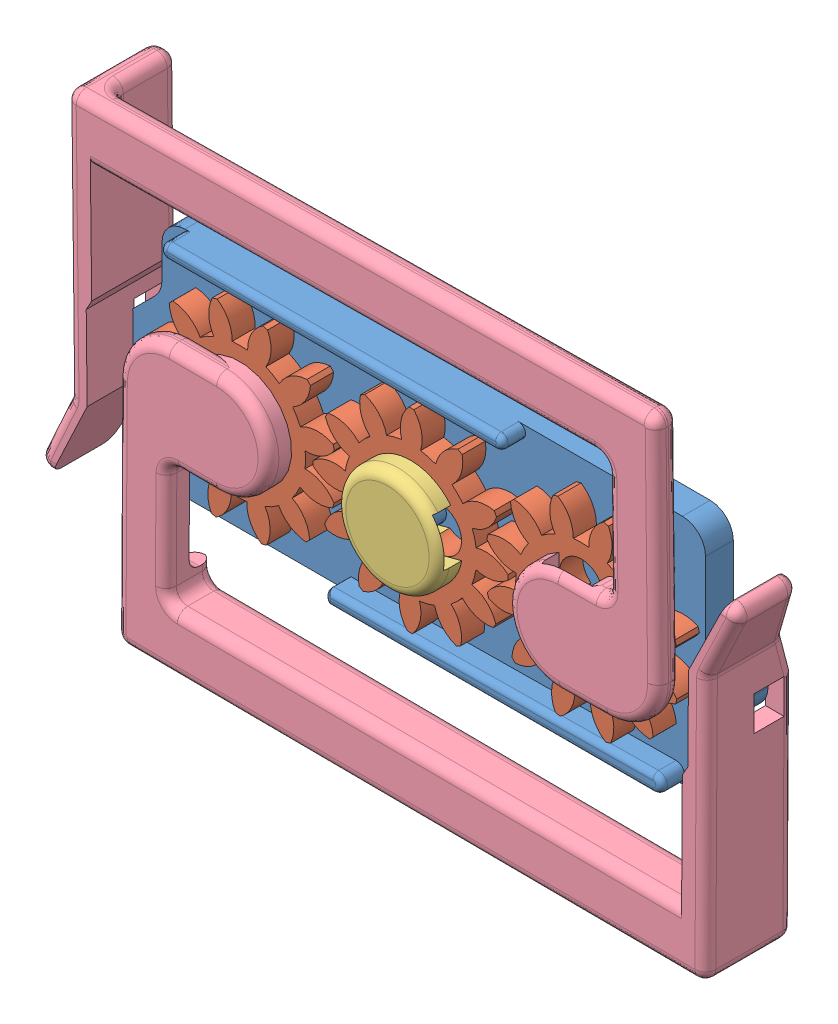
SolidWorks assembly WebCoupler, configuration Default. Lengths in mm.
Overall size (76.9 51.21 9.65).
7 component instances, 4 part files, 17 mates.
Components (placement in the parent):
- BasePlate-1: BasePlate [Default] at (-2.9894 14.8162 46.0364) size (67.3 25.47 7.37)
- WebGear-1: WebGear [Default] at (26.8556 27.5162 51.6244) x (0.251002 -0.967986 0) z (0 0 -1) size (20.81 20.81 2.54)
- WebGear-2: WebGear [Default] at (45.6516 27.5162 51.6244) x (0.999938 0.011168 0) z (0 0 -1) size (20.81 20.81 2.54)
- WebGear-3: WebGear [Default] at (8.0596 27.5162 51.6244) x (-0.999982 0.00603 0) z (0 0 -1) size (20.81 20.81 2.54)
- CapturePlate-1: CapturePlate [Default] at (27.6271 28.2686 54.1644) x (0.251002 -0.967986 0) z (0 0 -1) size (11.42 11.3 5.08)
- WebArm-2: WebArm [Default] at (8.6151 26.6036 54.1644) x (-0.999982 0.00603 0) z (0 0 -1) size (67.99 37.46 9.65)
- WebArm-4: WebArm [Default] at (45.0804 28.4191 54.1644) x (0.999938 0.011168 0) z (0 0 -1) size (67.99 37.46 9.65)
Mates (geometry in assembly coordinates):
- Coincident1: coincident anti-aligned: plane of BasePlate-1 through (-2.9894 14.8162 49.0844) normal (0 0 1); plane of WebGear-3 through (10.1295 31.2966 49.0844) normal (0 0 -1)
- Concentric2: concentric anti-aligned: cylinder of BasePlate-1 through (8.0596 27.5162 51.7514) axis (0 0 -1) radius 1.397; cylinder of WebGear-3 through (8.0596 27.5162 49.0844) axis (0 0 1) radius 1.524
- Coincident2: coincident anti-aligned: plane of BasePlate-1 through (-2.9894 14.8162 49.0844) normal (0 0 1); plane of WebGear-1 through (22.6703 28.5457 49.0844) normal (0 0 -1)
- Concentric3: concentric anti-aligned: cylinder of BasePlate-1 through (26.8556 27.5162 51.7514) axis (0 0 -1) radius 1.397; cylinder of WebGear-1 through (26.8556 27.5162 49.0844) axis (0 0 1) radius 1.524
- Coincident3: coincident anti-aligned: plane of BasePlate-1 through (-2.9894 14.8162 49.0844) normal (0 0 1); plane of WebGear-2 through (43.647 23.7007 49.0844) normal (0 0 -1)
- Concentric4: concentric anti-aligned: cylinder of BasePlate-1 through (45.6516 27.5162 51.7514) axis (0 0 -1) radius 1.397; cylinder of WebGear-2 through (45.6516 27.5162 49.0844) axis (0 0 1) radius 1.524
- GearMate5: gear = 3.048 : 3.048 mm: circle of WebGear-1; circle of WebGear-3
- GearMate6: gear = 3.048 : 3.048 mm: circle of WebGear-1; circle of WebGear-2
- Concentric7: concentric anti-aligned: circle of BasePlate-1; circle of CapturePlate-1
- Parallel2: parallel aligned: line of WebGear-1 through (27.6844 24.3199 49.0844) axis (-0.251002 0.967986 0); line of CapturePlate-1 through (27.7355 24.3331 49.0844) axis (-0.251002 0.967986 0)
- Coincident15: coincident anti-aligned: plane of WebGear-1 through (22.6703 28.5457 51.6244) normal (0 0 1); circle of CapturePlate-1
- Coincident17: coincident anti-aligned: plane of BasePlate-1 through (-2.9894 14.8162 49.0844) normal (0 0 1); plane of CapturePlate-1 through (28.3993 24.5053 49.0844) normal (0 0 -1)
- Coincident21: coincident: moEndPointRef_w of WebGear-3; moEndPointRef_w of WebArm-2
- Parallel5: parallel aligned: line of WebGear-3 through (4.7576 27.5361 51.6244) axis (0.999982 -0.00603 0); line of WebArm-2 through (4.7839 27.5096 51.6244) axis (0.999982 -0.00603 0)
- Coincident24: coincident anti-aligned: plane of WebGear-3 through (10.1295 31.2966 51.6244) normal (0 0 1); circle of WebArm-2
- Coincident33: coincident: moEndPointRef_w of WebGear-2; moEndPointRef_w of WebArm-4
- Parallel7: parallel aligned: line of WebGear-2 through (48.9534 27.5531 51.6244) axis (-0.999938 -0.011168 0); line of WebArm-4 through (48.9267 27.5791 51.6244) axis (-0.999938 -0.011168 0)
